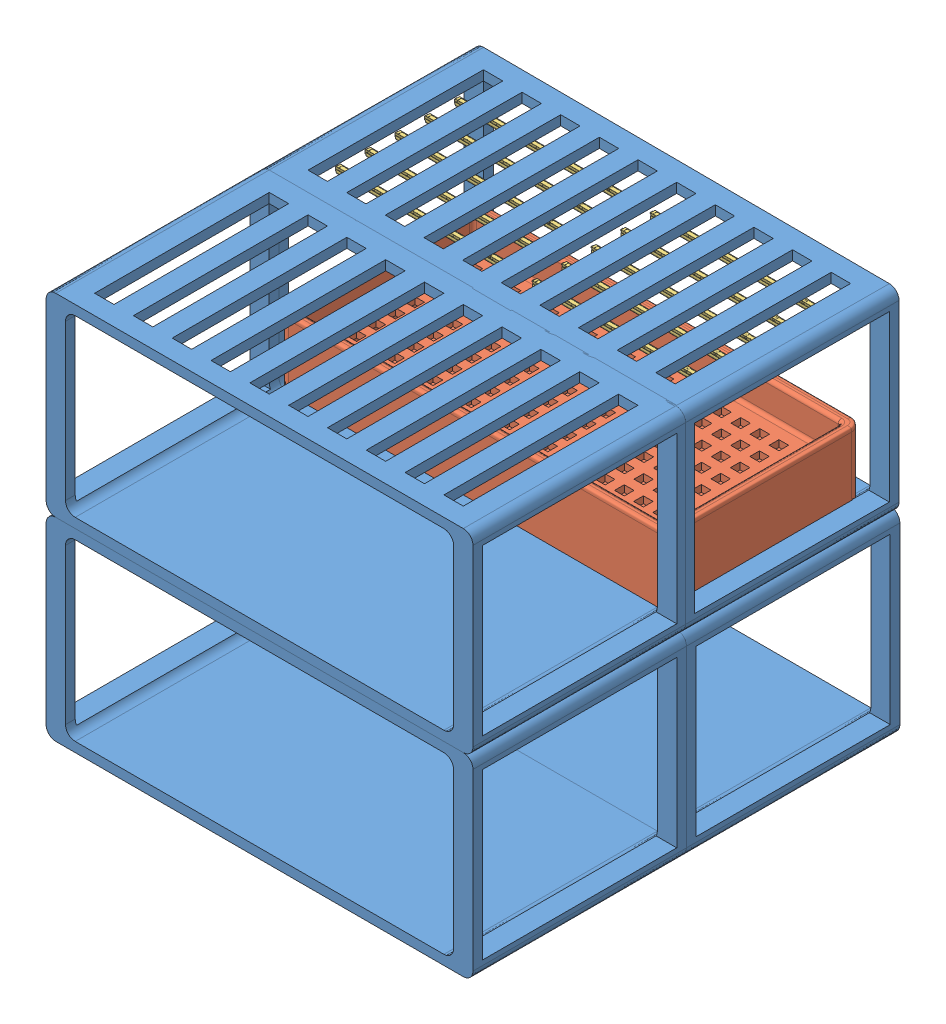
SolidWorks assembly Crate Assembly, configuration Default. Lengths in mm.
Overall size (2204.74 2000 2200.21).
15 component instances, 3 part files, 14 mates.
Components (placement in the parent):
- Growing Crate-1: Growing Crate [Default] at (1998.7974 950.4228 1201.5723) size (2200 1000 1100)
- Growing Crate-2: Growing Crate [Default] at (1998.7974 1950.4228 1201.5723) size (2200 1000 1100)
- Growing box-1: Growing box [Default] at (1898.7974 2000.4228 201.5723) size (2000.2 350.1 1000.2)
- Growing Crate-3: Growing Crate [Default] at (-201.2022 1950.4228 1201.3561) x (-0.999991 0 -0.004324) z (0.004324 0 -0.999991) size (2200 1000 1100)
- Growing Crate-4: Growing Crate [Default] at (-201.2026 950.4228 1201.5723) x (-1 0 0) z (0 0 -1) size (2200 1000 1100)
- Slimlite-1: Slimlite [Light On] at (1852.4382 2900.4228 363.857) x (0.999991 0 0.004324) z (-0.004324 0 0.999991) size (889 35.89 25.69)
- Slimlite-2: Slimlite [Light On] at (1852.4382 2900.4228 515.857) x (0.999991 0 0.004324) z (-0.004324 0 0.999991) size (889 35.89 25.69)
- Slimlite-3: Slimlite [Light On] at (1852.4382 2900.4228 667.857) x (0.999991 0 0.004324) z (-0.004324 0 0.999991) size (889 35.89 25.69)
- Slimlite-4: Slimlite [Light On] at (1852.4382 2900.4228 819.857) x (0.999991 0 0.004324) z (-0.004324 0 0.999991) size (889 35.89 25.69)
- Slimlite-5: Slimlite [Light On] at (1852.4382 2900.4228 971.857) x (0.999991 0 0.004324) z (-0.004324 0 0.999991) size (889 35.89 25.69)
- Slimlite-6: Slimlite [Light On] at (-47.4456 2900.4228 332.8674) x (-0.999991 0 -0.004324) z (0.004324 0 -0.999991) size (889 35.89 25.69)
- Slimlite-7: Slimlite [Light On] at (-48.76 2900.4228 484.8617) x (-0.999991 0 -0.004324) z (0.004324 0 -0.999991) size (889 35.89 25.69)
- Slimlite-8: Slimlite [Light On] at (-50.0744 2900.4228 636.856) x (-0.999991 0 -0.004324) z (0.004324 0 -0.999991) size (889 35.89 25.69)
- Slimlite-9: Slimlite [Light On] at (-51.3888 2900.4228 788.8503) x (-0.999991 0 -0.004324) z (0.004324 0 -0.999991) size (889 35.89 25.69)
- Slimlite-10: Slimlite [Light On] at (-52.7032 2900.4228 940.8446) x (-0.999991 0 -0.004324) z (0.004324 0 -0.999991) size (889 35.89 25.69)
Mates (geometry in assembly coordinates):
- Coincident1: coincident anti-aligned: line of Growing Crate-1 through (1948.7974 1950.4228 2301.5723) axis (-1 0 0); line of Growing Crate-2 through (-151.2026 1950.4228 2301.5723) axis (1 0 0)
- Coincident2: coincident: point of Growing Crate-1; point of Growing Crate-2
- Coincident4: coincident anti-aligned: plane of Growing Crate-2 through (1898.7974 2900.4228 1201.5723) normal (-1 0 0); plane of Growing box-1 through (1898.7974 2000.4228 1201.5723) normal (1 0 0)
- Coincident5: coincident: point of Growing Crate-2; point of Growing Crate-3
- Coincident6: coincident: point of Growing Crate-1; point of Growing Crate-4
- Coincident8: coincident anti-aligned: plane of Growing Crate-2 through (-101.2026 2000.4228 1201.5723) normal (0 1 0); plane of Growing box-1 through (1898.7974 2000.4228 1201.5723) normal (0 -1 0)
- Coincident9: coincident anti-aligned: plane of Growing Crate-2 through (-101.2026 2900.4228 1201.5723) normal (1 0 0); plane of Growing box-1 through (-101.2026 2000.4228 1201.5723) normal (-1 0 0)
- Coincident10: coincident anti-aligned: plane of Growing Crate-3 through (-196.446 1950.4228 101.3664) normal (0 -1 0); plane of Growing Crate-4 through (-201.2026 1950.4228 101.5723) normal (0 1 0)
- Coincident11: coincident anti-aligned: plane of Growing Crate-1 through (1998.7974 950.4228 1201.5723) normal (0 0 -1); plane of Growing Crate-4 through (-201.2026 950.4228 1201.5723) normal (0 0 1)
- Coincident12: coincident aligned: plane of Growing Crate-1 through (1998.7974 950.4228 2301.5723) normal (0 -1 0); plane of Growing Crate-4 through (-201.2026 950.4228 101.5723) normal (0 -1 0)
- LimitDistance1: limit distance = 0 mm: line of Growing Crate-2 through (-201.2026 2900.4228 1201.5723) axis (0 -1 0); plane of Growing box-1 through (1898.7974 2000.4228 1201.5723) normal (0 0 1)
- Coincident15: coincident anti-aligned: plane of Growing Crate-3 through (1898.7782 2900.4228 1210.436) normal (0 -1 0); plane of Slimlite-1 through (972.3375 2900.4228 359.7976) normal (0 1 0)
- Distance2: distance = 50 mm anti-aligned: plane of Slimlite-1 through (1852.4382 2900.4228 363.857) normal (0.999991 0 0.004324); plane of Growing Crate-3 through (1898.7782 2900.4228 1210.436) normal (-0.999991 0 -0.004324)
- Distance3: distance = 230 mm aligned: plane of Slimlite-1 through (1754.7512 2894.1559 339.8051) normal (0.004324 0 -0.999991); plane of Growing Crate-3 through (-196.446 1950.4228 101.3664) normal (0.004324 0 -0.999991)
